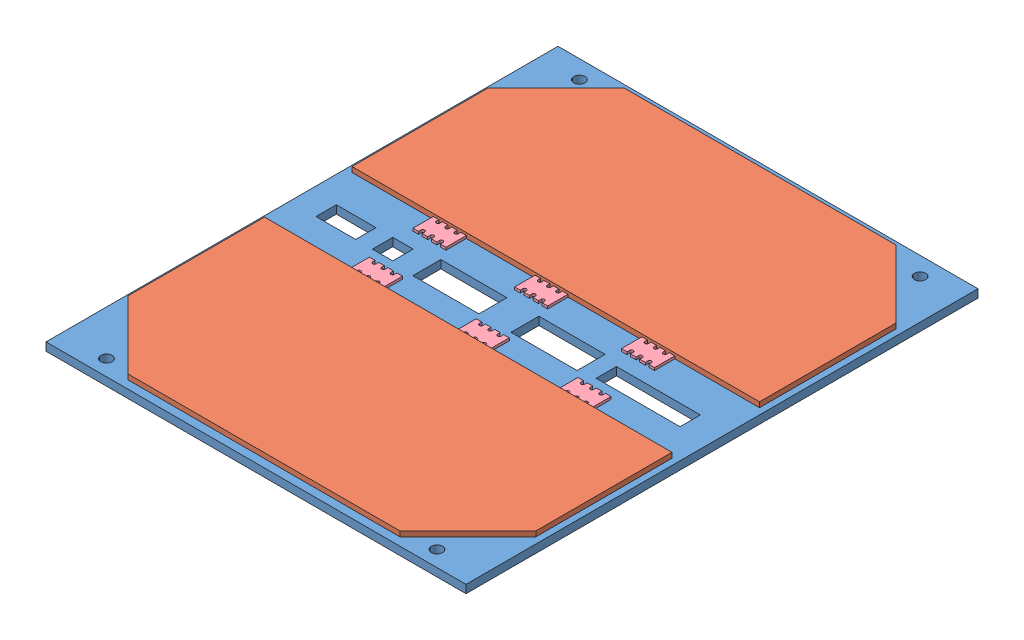
SolidWorks assembly B3_+X_panel, configuration Default. Lengths in mm.
Overall size (82.6 7.1 100.7).
10 component instances, 4 part files, 27 mates.
Components (placement in the parent):
- B3_+X_panel-2: B3_+X_panel [Default] at (0.7611 19.6493 -22.1375) size (82.6 1.6 100.7)
- Solar panel-2: Solar panel [Default] at (37.4682 21.2493 -21.6831) size (80.15 1 40.15)
- Solar panel-3: Solar panel [Default] at (11.5339 21.2493 15.1831) x (-1 0 0) z (0 0 -1) size (80.15 1 40.15)
- Solar panel_f-1: Solar panel_f [Default] at (12.5011 15.1493 38.4) x (0 0 -1) z (-1 0 0) size (3.7 4.5 24)
- Solar panel_connector-2: Solar panel_connector [Default] at (6.9261 21.2493 -11.85) size (6.5 0.5 4)
- Solar panel_connector-3: Solar panel_connector [Default] at (48.5761 21.2493 1.35) size (6.5 0.5 4)
- Solar panel_connector-4: Solar panel_connector [Default] at (28.5761 21.2493 1.35) size (6.5 0.5 4)
- Solar panel_connector-5: Solar panel_connector [Default] at (7.5761 21.2493 1.35) size (6.5 0.5 4)
- Solar panel_connector-6: Solar panel_connector [Default] at (47.9261 21.2493 -11.85) size (6.5 0.5 4)
- Solar panel_connector-8: Solar panel_connector [Default] at (26.9261 21.2493 -11.85) size (6.5 0.5 4)
Mates (geometry in assembly coordinates):
- Coincident4: coincident anti-aligned: plane of B3_+X_panel-2 through (0.7611 21.2493 -22.1375) normal (0 1 0); plane of Solar panel-2 through (37.4682 21.2493 -21.6831) normal (0 -1 0)
- Coincident7: coincident anti-aligned: plane of B3_+X_panel-2 through (0.7611 21.2493 -22.1375) normal (0 1 0); plane of Solar panel-3 through (11.5339 21.2493 15.1831) normal (0 -1 0)
- Coincident8: coincident aligned: plane of Solar panel-2 through (-15.5739 22.2493 -11.85) normal (-1 0 0); plane of Solar panel-3 through (-15.5739 22.2493 32.15) normal (-1 0 0)
- Coincident27: coincident anti-aligned: plane of B3_+X_panel-2 through (0.7611 19.6493 -22.1375) normal (0 -1 0); plane of Solar panel_f-1 through (12.5011 19.6493 38.4) normal (0 1 0)
- 距離1: distance = 8.7 mm aligned: plane of Solar panel_f-1 through (36.5011 15.1493 38.4) normal (0 0 1); plane of B3_+X_panel-2 through (0.7611 19.6493 47.1) normal (0 0 1)
- 距離3: distance = 1.6 mm aligned: plane of Solar panel-2 through (-2.2239 22.2493 -52) normal (0 0 -1); plane of B3_+X_panel-2 through (0.7611 19.6493 -53.6) normal (0 0 -1)
- 距離4: distance = 1.6 mm aligned: plane of B3_+X_panel-2 through (0.7611 19.6493 47.1) normal (0 0 1); plane of Solar panel-3 through (51.2261 22.2493 45.5) normal (0 0 1)
- Distance18: distance = 1.225 mm aligned: plane of Solar panel-2 through (-15.5739 22.2493 -11.85) normal (-1 0 0); plane of B3_+X_panel-2 through (-16.7989 19.6493 -53.6) normal (-1 0 0)
- Distance19: distance = 29.3 mm aligned: plane of Solar panel_f-1 through (36.5011 15.1493 38.4) normal (1 0 0); plane of B3_+X_panel-2 through (65.8011 19.6493 47.1) normal (1 0 0)
- 一致1: coincident anti-aligned: plane of B3_+X_panel-2 through (0.7611 21.2493 -22.1375) normal (0 1 0); plane of Solar panel_connector-8 through (25.4761 21.2493 -8.35) normal (0 -1 0)
- 一致2: coincident anti-aligned: plane of B3_+X_panel-2 through (0.7611 21.2493 -22.1375) normal (0 1 0); plane of Solar panel_connector-2 through (5.4761 21.2493 -8.35) normal (0 -1 0)
- 一致3: coincident anti-aligned: plane of B3_+X_panel-2 through (0.7611 21.2493 -22.1375) normal (0 1 0); plane of Solar panel_connector-3 through (47.1261 21.2493 4.85) normal (0 -1 0)
- 一致4: coincident anti-aligned: plane of B3_+X_panel-2 through (0.7611 21.2493 -22.1375) normal (0 1 0); plane of Solar panel_connector-4 through (27.1261 21.2493 4.85) normal (0 -1 0)
- 一致5: coincident anti-aligned: plane of B3_+X_panel-2 through (0.7611 21.2493 -22.1375) normal (0 1 0); plane of Solar panel_connector-5 through (6.1261 21.2493 4.85) normal (0 -1 0)
- 一致6: coincident anti-aligned: plane of B3_+X_panel-2 through (0.7611 21.2493 -22.1375) normal (0 1 0); plane of Solar panel_connector-6 through (46.4761 21.2493 -8.35) normal (0 -1 0)
- 一致7: coincident: plane of Solar panel-2 through (64.5761 22.2493 -11.85) normal (0 0 1); line of Solar panel_connector-2 through (3.3261 21.7493 -11.85) axis (-1 0 0)
- 一致8: coincident: plane of Solar panel-2 through (64.5761 22.2493 -11.85) normal (0 0 1); line of Solar panel_connector-8 through (23.3261 21.7493 -11.85) axis (-1 0 0)
- 一致9: coincident: plane of Solar panel-2 through (64.5761 22.2493 -11.85) normal (0 0 1); line of Solar panel_connector-6 through (46.1261 21.7493 -11.85) axis (-1 0 0)
- 一致13: coincident anti-aligned: plane of Solar panel-3 through (-15.5739 22.2493 5.35) normal (0 0 -1); plane of Solar panel_connector-3 through (45.6761 21.7493 5.35) normal (0 0 1)
- 一致14: coincident anti-aligned: plane of Solar panel-3 through (-15.5739 22.2493 5.35) normal (0 0 -1); plane of Solar panel_connector-4 through (24.9761 21.7493 5.35) normal (0 0 1)
- 一致15: coincident anti-aligned: plane of Solar panel-3 through (-15.5739 22.2493 5.35) normal (0 0 -1); plane of Solar panel_connector-5 through (3.9761 21.7493 5.35) normal (0 0 1)
- 距離11: distance = 16 mm: line of Solar panel-3 through (64.5761 22.2493 32.15) axis (0 0 -1); plane of Solar panel_connector-3 through (48.5761 21.7493 1.35) normal (1 0 0)
- 距離12: distance = 36 mm aligned: plane of Solar panel_connector-4 through (28.5761 21.7493 1.35) normal (1 0 0); plane of Solar panel-3 through (64.5761 22.2493 5.35) normal (1 0 0)
- 距離13: distance = 57 mm aligned: plane of Solar panel_connector-5 through (7.5761 21.7493 1.35) normal (1 0 0); plane of Solar panel-3 through (64.5761 22.2493 5.35) normal (1 0 0)
- 距離14: distance = 16 mm aligned: plane of Solar panel_connector-2 through (0.4261 21.7493 -11.85) normal (-1 0 0); plane of Solar panel-2 through (-15.5739 22.2493 -11.85) normal (-1 0 0)
- 距離15: distance = 36 mm aligned: plane of Solar panel_connector-8 through (20.4261 21.7493 -11.85) normal (-1 0 0); plane of Solar panel-2 through (-15.5739 22.2493 -11.85) normal (-1 0 0)
- 距離16: distance = 57 mm aligned: plane of Solar panel_connector-6 through (41.4261 21.7493 -11.85) normal (-1 0 0); plane of Solar panel-2 through (-15.5739 22.2493 -11.85) normal (-1 0 0)
